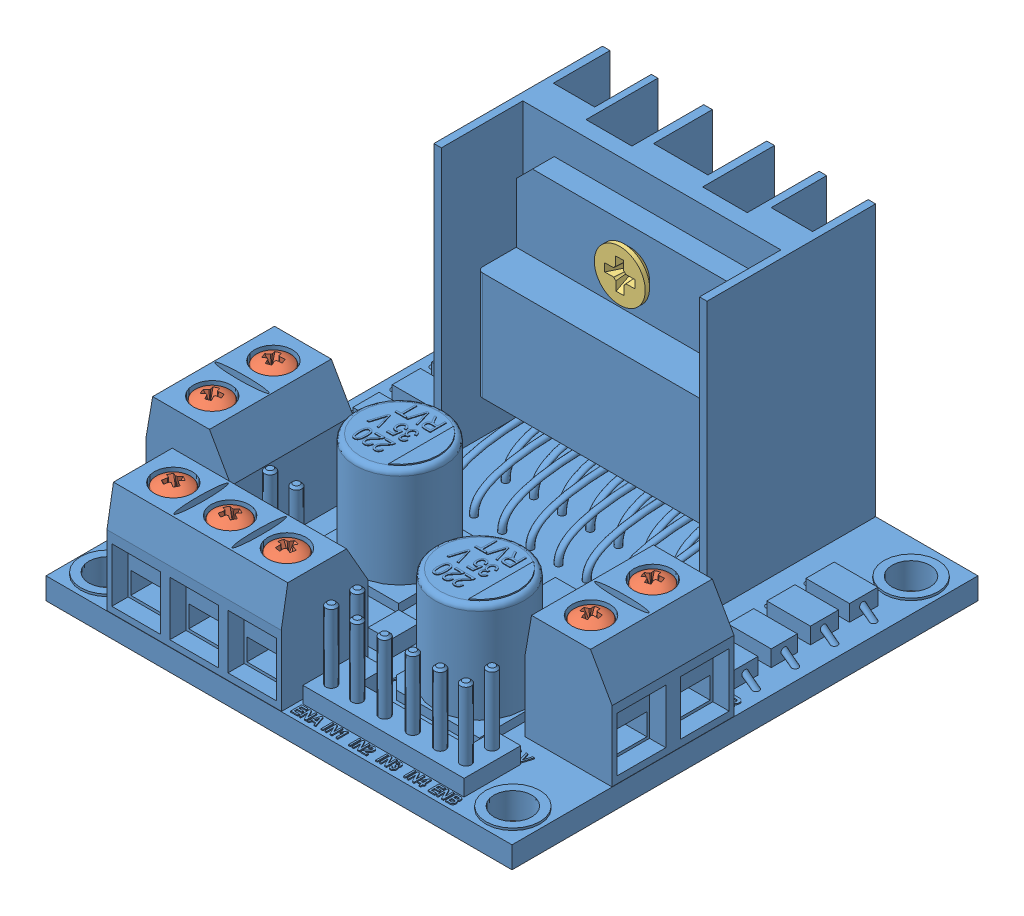
SolidWorks assembly L298N, configuration Default. Lengths in mm.
Overall size (43 28.01 43).
9 component instances, 3 part files, 16 mates.
Components (placement in the parent):
- L298N Stepper Motor Driver (Red)-1: L298N Stepper Motor Driver (Red) [Default] at (-89.3884 -13.295 48.5108) size (43 28.01 43)
- pan head cross recess screw_iso-1: pan head cross recess screw_iso [ISO 7045 - M1.6 x 4 - Z - 4N] at (-72.5884 -0.995 52.3243) x (0 -1 0) z (0.332966 0 0.942939) size (5.27 3.2 3.2)
- pan head cross recess screw_iso-3: pan head cross recess screw_iso [ISO 7045 - M1.6 x 4 - Z - 4N] at (-91.9801 -0.995 66.6875) x (0 -1 0) z (-0.208825 0 0.977953) size (5.27 3.2 3.2)
- pan head cross recess screw_iso-4: pan head cross recess screw_iso [ISO 7045 - M1.6 x 4 - Z - 4N] at (-97.2219 -0.995 66.6875) x (0 -1 0) z (-0.893472 0 -0.449119) size (5.27 3.2 3.2)
- pan head cross recess screw_iso-5: pan head cross recess screw_iso [ISO 7045 - M1.6 x 4 - Z - 4N] at (-102.4637 -0.995 66.6875) x (0 -1 0) z (-0.477141 0 0.878827) size (5.27 3.2 3.2)
- pan head cross recess screw_iso-6: pan head cross recess screw_iso [ISO 7045 - M1.6 x 4 - Z - 4N] at (-107.5884 -0.995 57.9688) x (0 -1 0) z (0.396742 0 0.91793) size (5.27 3.2 3.2)
- pan head cross recess screw_iso-7: pan head cross recess screw_iso [ISO 7045 - M1.6 x 4 - Z - 4N] at (-107.5884 -0.995 52.3243) x (0 -1 0) z (0.339075 0 0.940759) size (5.27 3.2 3.2)
- pan head cross recess screw_iso-8: pan head cross recess screw_iso [ISO 7045 - M1.6 x 4 - Z - 4N] at (-72.5884 -0.995 58.0188) x (0 -1 0) z (-0.984368 0 0.176126) size (5.27 3.2 3.2)
- countersunk flat head cross recess screw_iso-2: countersunk flat head cross recess screw_iso [ISO 7046-1 - M2.5 x 3 - Z - 3N] at (-89.8922 7.205 38.0625) x (0 0 -1) z (0.999801 0.019932 0) size (3 4.7 4.7)
Mates (geometry in assembly coordinates):
- Concentric1: concentric aligned: cylinder of L298N Stepper Motor Driver (Red)-1 through (-72.5884 -6.295 52.3243) axis (0 1 0) radius 1.75; cylinder of pan head cross recess screw_iso-1 through (-72.5884 24.405 52.3243) axis (0 1 0) radius 1.6
- Concentric3: concentric aligned: cylinder of L298N Stepper Motor Driver (Red)-1 through (-91.9801 -6.295 66.6875) axis (0 1 0) radius 1.75; cylinder of pan head cross recess screw_iso-3 through (-91.9801 24.405 66.6875) axis (0 1 0) radius 1.6
- Concentric4: concentric aligned: cylinder of L298N Stepper Motor Driver (Red)-1 through (-97.2219 -6.295 66.6875) axis (0 1 0) radius 1.75; cylinder of pan head cross recess screw_iso-4 through (-97.2219 24.405 66.6875) axis (0 1 0) radius 1.6
- Concentric5: concentric aligned: cylinder of L298N Stepper Motor Driver (Red)-1 through (-102.4637 -6.295 66.6875) axis (0 1 0) radius 1.75; cylinder of pan head cross recess screw_iso-5 through (-102.4637 24.405 66.6875) axis (0 1 0) radius 1.6
- Concentric6: concentric aligned: cylinder of L298N Stepper Motor Driver (Red)-1 through (-107.5884 -6.295 57.9688) axis (0 1 0) radius 1.75; cylinder of pan head cross recess screw_iso-6 through (-107.5884 24.405 57.9688) axis (0 1 0) radius 1.6
- Concentric7: concentric aligned: cylinder of L298N Stepper Motor Driver (Red)-1 through (-107.5884 -6.295 52.3243) axis (0 1 0) radius 1.75; cylinder of pan head cross recess screw_iso-7 through (-107.5884 24.405 52.3243) axis (0 1 0) radius 1.6
- Concentric8: concentric aligned: cylinder of L298N Stepper Motor Driver (Red)-1 through (-72.5884 -6.295 58.0188) axis (0 1 0) radius 1.75; cylinder of pan head cross recess screw_iso-8 through (-72.5884 24.405 58.0188) axis (0 1 0) radius 1.6
- Coincident11: coincident anti-aligned: plane of L298N Stepper Motor Driver (Red)-1 through (-72.5884 -6.295 52.3243) normal (0 1 0); plane of pan head cross recess screw_iso-1 through (-71.834 -6.295 52.0579) normal (0 -1 0)
- Coincident12: coincident anti-aligned: plane of L298N Stepper Motor Driver (Red)-1 through (-72.5884 -6.295 58.0188) normal (0 1 0); plane of pan head cross recess screw_iso-8 through (-72.4475 -6.295 58.8063) normal (0 -1 0)
- Coincident13: coincident anti-aligned: plane of L298N Stepper Motor Driver (Red)-1 through (-91.9801 -6.295 66.6875) normal (0 1 0); plane of pan head cross recess screw_iso-3 through (-91.1978 -6.295 66.8545) normal (0 -1 0)
- Coincident14: coincident anti-aligned: plane of L298N Stepper Motor Driver (Red)-1 through (-97.2219 -6.295 66.6875) normal (0 1 0); plane of pan head cross recess screw_iso-4 through (-97.5812 -6.295 67.4023) normal (0 -1 0)
- Coincident15: coincident anti-aligned: plane of L298N Stepper Motor Driver (Red)-1 through (-102.4637 -6.295 66.6875) normal (0 1 0); plane of pan head cross recess screw_iso-5 through (-101.7606 -6.295 67.0692) normal (0 -1 0)
- Coincident16: coincident anti-aligned: plane of L298N Stepper Motor Driver (Red)-1 through (-107.5884 -6.295 57.9688) normal (0 1 0); plane of pan head cross recess screw_iso-6 through (-106.854 -6.295 57.6514) normal (0 -1 0)
- Coincident17: coincident anti-aligned: plane of L298N Stepper Motor Driver (Red)-1 through (-107.5884 -6.295 52.3243) normal (0 1 0); plane of pan head cross recess screw_iso-7 through (-106.8358 -6.295 52.053) normal (0 -1 0)
- Concentric13: concentric aligned: cylinder of L298N Stepper Motor Driver (Red)-1 through (-89.8922 7.205 30.1127) axis (0 0 1) radius 1.75; cylinder of countersunk flat head cross recess screw_iso-2 through (-89.8922 7.205 44.4125) axis (0 0 1) radius 1.25
- Coincident20: coincident anti-aligned: plane of L298N Stepper Motor Driver (Red)-1 through (-101.8441 13.705 35.0625) normal (0 0 1); plane of countersunk flat head cross recess screw_iso-2 through (-89.9172 8.4548 35.0625) normal (0 0 -1)
